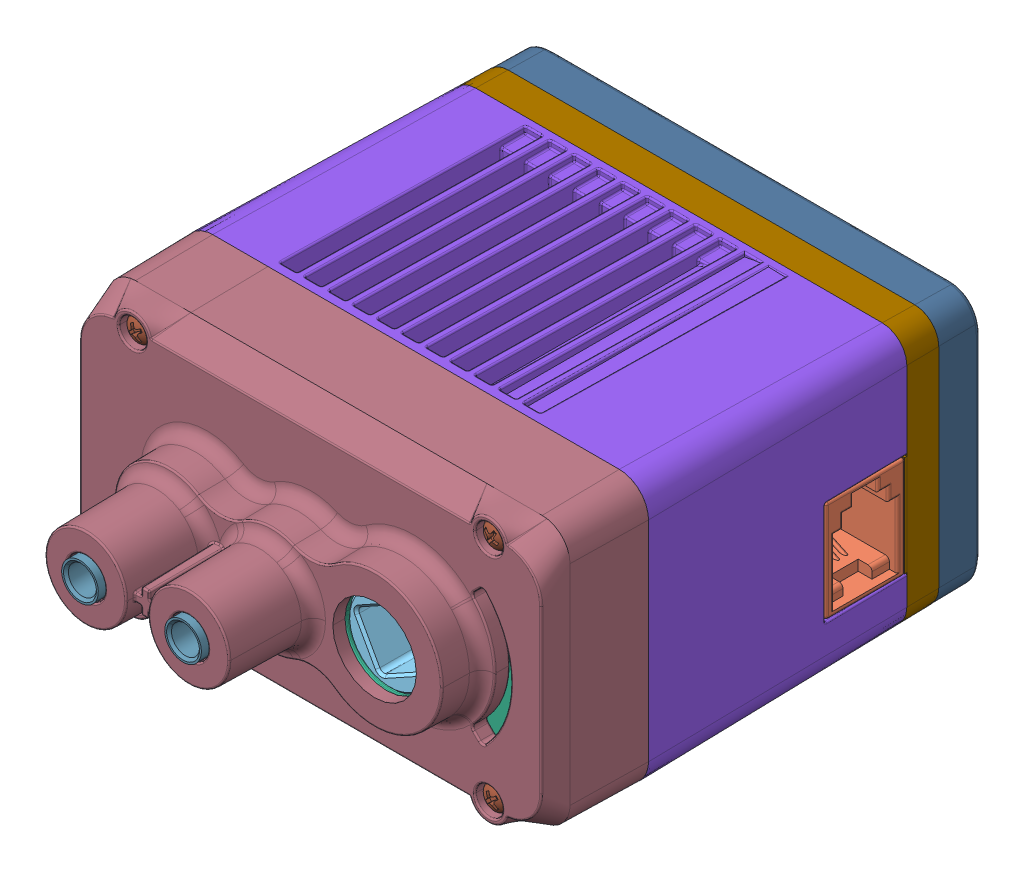
SolidWorks assembly V5_Smart_Motor_276-4840, configuration Default. Lengths in mm.
Overall size (59.01 35.33 72.31).
26 component instances, 15 part files, 0 mates.
Components (placement in the parent):
- V5_Smart_Motor_276-4840.STEP-1: V5_Smart_Motor_276-4840.STEP [Default] at origin size (59.01 35.33 72.31)
  - 276-4840-900 Rev6_Instruction.STEP-1: 276-4840-900 Rev6_Instruction.STEP [Default] at (-14.3 0 -17.2) size (52.79 15.94 38.15)
    - 276-4840-901 Rev6.STEP-1: 276-4840-901 Rev6.STEP [Default] at (10.75 -10.05 17.8) x (-1 0 0) z (0 0 1) size (49.9 1.6 38.15)
    - 276-4840-902 Rev2.STEP-1: 276-4840-902 Rev2.STEP [Default] at (31.25 -9.25 6.2) x (0 0 -1) z (0 -1 0) size (10.35 11.39 15.94)
    - 276-4840-022 Rev4.STEP-1: 276-4840-022 Rev4.STEP [Default] at (31.25 -9.25 6.2) x (0 0 -1) z (1 0 0) size (10.26 9.1 5.51)
  - 276-4840-110 Rev10_Instruction.STEP-1: 276-4840-110 Rev10_Instruction.STEP [Default] at (12.7 0 14.7) size (35.33 35.33 31.1)
    - 276-4840-061 Rev7_Ring_Gear_Fixed01 .6 Rev3.STEP-1: 276-4840-061 Rev7_Ring_Gear_Fixed01 .6 Rev3.STEP [Default] at origin size (28.79 28.39 24.6)
    - 276-4840-018 Rev6.STEP-1: 276-4840-018 Rev6.STEP [Default] at (0 0 6.7) x (-0.483174 0.875524 0) z (0 0 1) size (26 26 12.3)
    - 276-4840-059 Rev2.STEP-1: 276-4840-059 Rev2.STEP [Default] at (0 0 10.3) size (28.4 28.4 8.5)
    - 276-4840-062 Rev1.STEP-1: 276-4840-062 Rev1.STEP [Default] at (-12.1353 8.8168 12.3) x (0.956835 -0.290632 0) z (-0.290632 -0.956835 0) size (3.2 6.56 3.2)
    - 276-4840-062 Rev1.STEP-2: 276-4840-062 Rev1.STEP [Default] at (12.1353 8.8168 12.3) x (0.978427 0.206591 0) z (0.206591 -0.978427 0) size (3.2 6.56 3.2)
    - 276-4840-062 Rev1.STEP-3: 276-4840-062 Rev1.STEP [Default] at (-12.1353 -8.8168 12.3) x (0.72563 0.688086 0) z (0.688086 -0.72563 0) size (3.2 6.56 3.2)
  - 276-4840-001 Rev38.STEP-1: 276-4840-001 Rev38.STEP [Default] at origin size (57.3 33 46.9)
  - 276-4840-005 Rev27.STEP-1: 276-4840-005 Rev27.STEP [Default] at (0 0 -17.95) size (56.17 31.87 12.9)
  - 276-4840-004 Rev16.STEP-1: 276-4840-004 Rev16.STEP [Default] at (0 0 -19.2) size (56.01 31.71 9.21)
  - 276-4840-015 Rev7.STEP-1: 276-4840-015 Rev7.STEP [Default] at (-21.95 14 27.9) x (-0.85131 -0.524663 0) z (-0.524663 0.85131 0) size (3.2 17.55 3.2)
  - 276-4840-015 Rev7.STEP-2: 276-4840-015 Rev7.STEP [Default] at (21.95 -14 27.9) x (-0.777574 -0.628792 0) z (-0.628792 0.777574 0) size (3.2 17.55 3.2)
  - 276-4840-015 Rev7.STEP-3: 276-4840-015 Rev7.STEP [Default] at (21.95 14 27.9) x (0.476859 0.87898 0) z (0.87898 -0.476859 0) size (3.2 17.55 3.2)
  - 276-4840-009 Rev3.STEP-1: 276-4840-009 Rev3.STEP [Default] at (25.45 13.5 15.7) x (0.19987 -0.979823 0) z (-0.979823 -0.19987 0) size (3.4 41.31 4.34)
  - 276-4840-009 Rev3.STEP-2: 276-4840-009 Rev3.STEP [Default] at (-25.45 -13.5 15.7) x (-0.998855 0.047836 0) z (0.047836 0.998855 0) size (3.4 41.31 4.34)
  - 276-4840-009 Rev3.STEP-3: 276-4840-009 Rev3.STEP [Default] at (25.45 -13.5 15.7) x (-0.975374 0.220559 0) z (0.220559 0.975374 0) size (3.4 41.31 4.34)
  - 276-4840-009 Rev3.STEP-4: 276-4840-009 Rev3.STEP [Default] at (-25.45 13.5 15.7) x (-0.922256 0.38658 0) z (0.38658 0.922256 0) size (3.4 41.31 4.34)
  - 276-4840-003 Rev27.STEP-1: 276-4840-003 Rev27.STEP [Default] at (0 0 16.2) size (57.3 33 28.01)
  - 276-4840-043 Rev8.STEP-1: 276-4840-043 Rev8.STEP [Default] at (-12.7 0 36.2) x (-0.5 -0.866025 0) z (-0.866025 0.5 0) size (6.3 15.2 7.21)
  - 276-4840-043 Rev8.STEP-2: 276-4840-043 Rev8.STEP [Default] at (0 0 36.2) x (-0.5 -0.866025 0) z (-0.866025 0.5 0) size (6.3 15.2 7.21)
  - 276-4840-025 Rev19.STEP-1: 276-4840-025 Rev19.STEP [Default] at (12.7 0 -22.63) x (-0.993315 0.115437 0) z (0 0 1) size (14.82 14.83 35.18)
